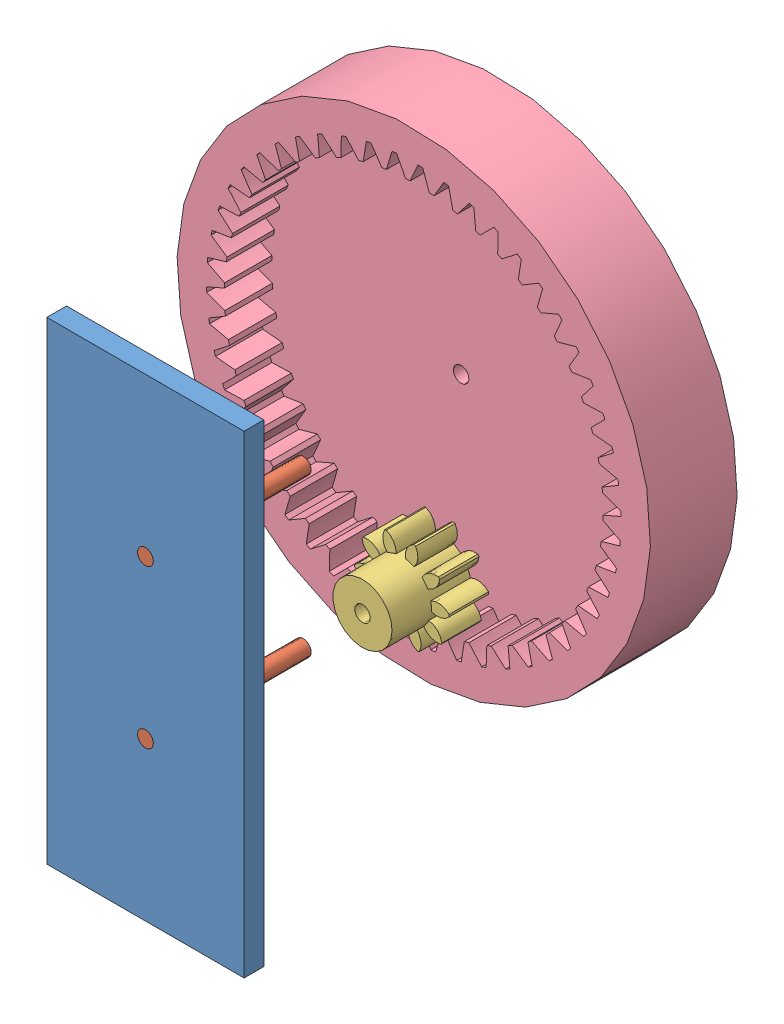
SolidWorks assembly Assemblage1, configuration Défaut. Lengths in mm.
Overall size (168.37 168.37 90).
5 component instances, 4 part files, 9 mates.
Components (placement in the parent):
- Support_Axes-1: Support_Axes [Défaut] at (-83.4318 -2.555 -2.5) size (50 120 5)
- axe-1: axe [Défaut] at (-83.4318 -22.555 -37.5) size (4 4 40)
- axe-2: axe [Défaut] at (-83.4318 17.445 -37.5) x (0.455948 -0.890007 0) z (0 0 1) size (4 4 40)
- RoueDente_externe-1: RoueDente_externe [DIN - Spur gear 2M 10T 20PA 10FW ---S10B50H20L4.0N] at (-83.4318 -22.555 -62.5001) x (0 0 -1) z (-0.783262 -0.621691 0) size (20 22.98 24)
- RoueDente_interne-1: RoueDente_interne [DIN - Internal spur gear 2M 50T 20PA 12FW ---S50S120OD 1.0AF] at (-83.4318 17.445 -65.5) x (0 0 -1) z (0.790044 -0.61305 0) size (22 120 120)
Mates (geometry in assembly coordinates):
- Coaxiale2: concentric aligned: cylinder of Support_Axes-1 through (-83.4318 17.445 2.5) axis (0 0 -1) radius 2; cylinder of axe-2 through (-83.4318 17.445 2.5) axis (0 0 -1) radius 2
- Coïncidente2: coincident aligned: plane of Support_Axes-1 through (-58.4318 57.445 2.5) normal (0 0 1); plane of axe-2 through (-83.4318 17.445 2.5) normal (0 0 1)
- Coaxiale3: concentric aligned: cylinder of Support_Axes-1 through (-83.4318 -22.555 2.5) axis (0 0 -1) radius 2; cylinder of axe-1 through (-83.4318 -22.555 2.5) axis (0 0 -1) radius 2
- Coïncidente3: coincident aligned: plane of Support_Axes-1 through (-58.4318 57.445 2.5) normal (0 0 1); plane of axe-1 through (-83.4318 -22.555 2.5) normal (0 0 1)
- Coaxiale4: concentric anti-aligned: cylinder of axe-2 through (-83.4318 17.445 2.5) axis (0 0 -1) radius 2; cylinder of RoueDente_interne-1 through (-83.4318 17.445 -87.5) axis (0 0 1) radius 2
- Distance1: distance = 50 mm aligned: plane of RoueDente_interne-1 through (-83.4318 17.445 -87.5) normal (0 0 -1); plane of axe-2 through (-83.4318 17.445 -37.5) normal (0 0 -1)
- Coaxiale5: concentric anti-aligned: cylinder of axe-1 through (-83.4318 -22.555 2.5) axis (0 0 -1) radius 2; cylinder of RoueDente_externe-1 through (-83.4318 -22.555 -82.5001) axis (0 0 1) radius 2
- Distance2: distance = 50 mm anti-aligned: plane of RoueDente_externe-1 through (-83.4318 -22.555 -52.5) normal (0 0 1); plane of Support_Axes-1 through (-58.4318 57.445 -2.5) normal (0 0 -1)
- Contr.Engrenages1: gear = 10 : 50 mm: cylinder of RoueDente_interne-1 through (-83.4318 17.445 -87.5) axis (0 0 1) radius 2; cylinder of RoueDente_externe-1 through (-83.4318 -22.555 -82.5001) axis (0 0 1) radius 2
